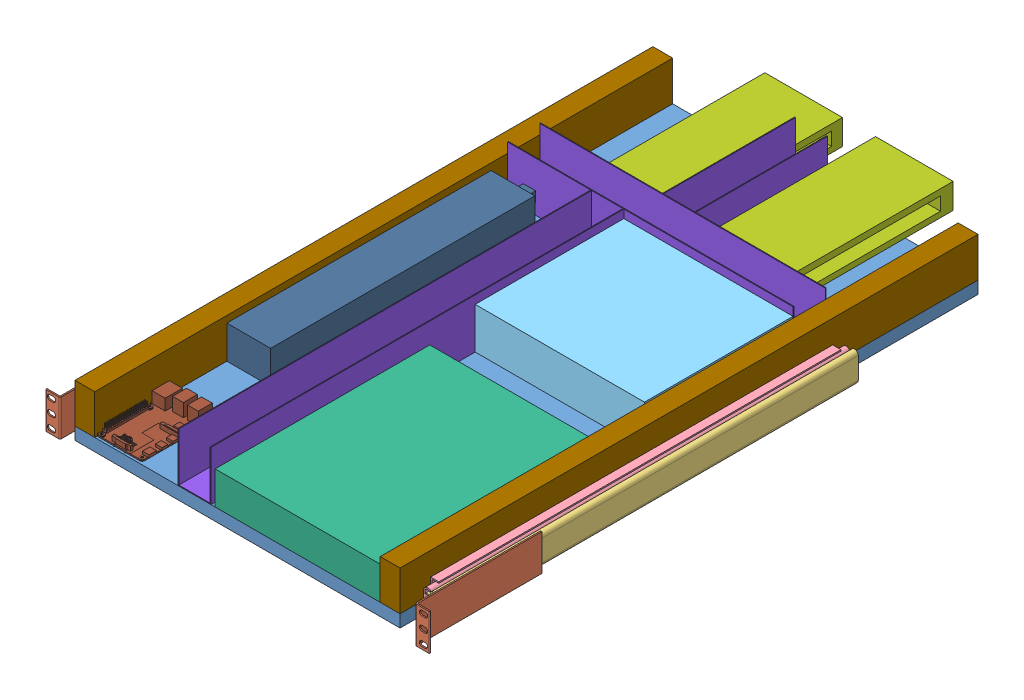
SolidWorks assembly Router-Schublade, configuration Standard. Lengths in mm.
Overall size (464.8 84.05 758).
20 component instances, 11 part files, 37 mates.
Components (placement in the parent):
- Platte-1: Platte [Standard] at (-201.5811 50.5043 900) size (393.8 15 700)
- Gleitschiene-Left-1: Gleitschiene-Left [Standard] at (-230.5216 -87.7457 847.2457) x (0 0 1) z (0 1 0) size (537 44.1 44)
  - winkel-1: winkel [Standard] at (51.9543 -6.5595 130.1) size (152.1 17.5 44)
  - Schine-1: Schine [Standard] at (-484.2457 10.9405 134.15) x (0 1 0) z (1 0 0) size (13.6 35 510)
  - Rolle-1: Rolle [Standard] at (-471.2457 35.9405 133.25) x (0 1 0) z (1 0 0) size (19.2 41.6 507)
- Gleitschiene-Right-1: Gleitschiene-Right [Standard] at (221.1594 215.5543 847.2457) x (0 0 1) z (0 -1 0) size (537 44.1 44.05)
  - winkel-1: winkel [Standard] at (51.9543 -6.5595 130.1) size (152.1 17.5 44)
  - Schine-1: Schine [Standard] at (-484.2457 10.9405 134.15) x (0 1 0) z (1 0 0) size (13.6 35 510)
  - Rolle-1: Rolle [Standard] at (15.7543 35.9405 170.05) x (0 1 0) z (-1 0 0) size (19.2 41.6 507)
- Modem-1: Modem [Standard] at (168.2189 115.5043 580) x (-1 0 0) z (0 -1 0) size (205 180 50)
- Router-1: Router [Standard] at (168.2189 65.5043 900) x (0 0 -1) z (1 0 0) size (260 40 200)
- Keystone Housing-1: Keystone Housing [Standard] at (-29.8854 65.5043 360) x (0 0 -1) z (1 0 0) size (218 30.5 94)
- Keystone Housing-2: Keystone Housing [Standard] at (10.1146 65.5043 142) x (0 0 1) z (-1 0 0) size (218 30.5 94)
- Kanal-1: Kanal [500] at (-56.7811 65.5043 400) size (40 60 500)
- Kanal-2: Kanal [160] at (-9.8854 65.5043 200) size (40 60 160)
- Seite-1: Seite [Standard] at (-201.5811 65.5043 200) size (24 48 700)
- Seite-2: Seite [Standard] at (168.2189 65.5043 200) size (24 48 700)
- Steckdose-1: Steckdose [Standard] at (-177.5811 65.5043 740) size (53 40 340)
- Kanal-3: Kanal [345,8] at (168.2189 65.5043 380) x (0 0 1) z (-1 0 0) size (40 60 345.8)
- Raspberry Pi 4 B-1: Raspberry Pi 4 B [默认] at (-135.4811 65.5043 851.3868) x (0 0 -1) z (0 1 0) size (86.92 58.6 19)
Mates (geometry in assembly coordinates):
- Deckungsgleich1: coincident anti-aligned: plane of Platte-1 through (-201.5811 65.5043 900) normal (-1 0 0); plane of Gleitschiene-Left-1/Rolle-1 through (-201.5811 45.5043 863) normal (1 0 0)
- Deckungsgleich2: coincident anti-aligned: plane of Platte-1 through (-201.5811 50.5043 900) normal (0 -1 0); plane of Gleitschiene-Left-1/Rolle-1 through (-192.9811 50.5043 863) normal (0 1 0)
- Abstand1: distance = 37 mm aligned: plane of Platte-1 through (-201.5811 65.5043 900) normal (0 0 1); plane of Gleitschiene-Left-1/Rolle-1 through (-194.5811 45.5043 863) normal (0 0 1)
- Deckungsgleich4: coincident anti-aligned: plane of Platte-1 through (192.2189 65.5043 900) normal (1 0 0); plane of Gleitschiene-Right-1/Rolle-1 through (192.2189 45.5043 376) normal (-1 0 0)
- Deckungsgleich5: coincident anti-aligned: plane of Platte-1 through (-201.5811 50.5043 900) normal (0 -1 0); plane of Gleitschiene-Right-1/Rolle-1 through (183.6189 50.5043 376) normal (0 1 0)
- Abstand2: distance = 37 mm aligned: plane of Platte-1 through (-201.5811 65.5043 900) normal (0 0 1); plane of Gleitschiene-Right-1/Rolle-1 through (185.2189 45.5043 863) normal (0 0 1)
- Deckungsgleich7: coincident anti-aligned: plane of Platte-1 through (-201.5811 65.5043 900) normal (0 1 0); plane of Modem-1 through (168.2189 65.5043 580) normal (0 -1 0)
- Deckungsgleich8: coincident anti-aligned: plane of Platte-1 through (-201.5811 65.5043 900) normal (0 1 0); plane of Router-1 through (168.2189 65.5043 900) normal (0 -1 0)
- Deckungsgleich11: coincident anti-aligned: plane of Platte-1 through (-201.5811 65.5043 900) normal (0 1 0); plane of Keystone Housing-2 through (10.1146 65.5043 142) normal (0 -1 0)
- Deckungsgleich15: coincident anti-aligned: plane of Platte-1 through (-201.5811 65.5043 900) normal (0 1 0); plane of Keystone Housing-1 through (-29.8854 65.5043 360) normal (0 -1 0)
- Deckungsgleich16: coincident anti-aligned: plane of Platte-1 through (-201.5811 65.5043 900) normal (0 1 0); plane of Kanal-1 through (-36.7811 65.5043 900) normal (0 -1 0)
- Deckungsgleich17: coincident aligned: plane of Platte-1 through (-201.5811 65.5043 900) normal (0 0 1); plane of Kanal-1 through (-56.7811 65.5043 900) normal (0 0 1)
- Deckungsgleich18: coincident anti-aligned: plane of Platte-1 through (-201.5811 65.5043 900) normal (0 1 0); plane of Kanal-2 through (10.1146 65.5043 360) normal (0 -1 0)
- Deckungsgleich19: coincident aligned: plane of Platte-1 through (-201.5811 65.5043 200) normal (0 0 -1); plane of Kanal-2 through (-9.8854 65.5043 200) normal (0 0 -1)
- Deckungsgleich20: coincident anti-aligned: plane of Platte-1 through (-201.5811 65.5043 900) normal (0 1 0); plane of Seite-1 through (-201.5811 65.5043 900) normal (0 -1 0)
- Deckungsgleich21: coincident anti-aligned: plane of Platte-1 through (-201.5811 65.5043 900) normal (0 1 0); plane of Seite-2 through (168.2189 65.5043 900) normal (0 -1 0)
- Deckungsgleich22: coincident aligned: plane of Platte-1 through (-201.5811 65.5043 900) normal (0 0 1); plane of Seite-2 through (168.2189 65.5043 900) normal (0 0 1)
- Deckungsgleich23: coincident aligned: plane of Platte-1 through (-201.5811 65.5043 900) normal (0 0 1); plane of Seite-1 through (-201.5811 65.5043 900) normal (0 0 1)
- Deckungsgleich24: coincident anti-aligned: plane of Gleitschiene-Left-1/Rolle-1 through (-201.5811 45.5043 863) normal (1 0 0); plane of Seite-1 through (-201.5811 65.5043 900) normal (-1 0 0)
- Deckungsgleich25: coincident anti-aligned: plane of Gleitschiene-Right-1/Rolle-1 through (192.2189 45.5043 376) normal (-1 0 0); plane of Seite-2 through (192.2189 65.5043 900) normal (1 0 0)
- Deckungsgleich27: coincident anti-aligned: plane of Router-1 through (168.2189 105.5043 900) normal (1 0 0); plane of Seite-2 through (168.2189 65.5043 900) normal (-1 0 0)
- Deckungsgleich28: coincident aligned: plane of Platte-1 through (-201.5811 65.5043 900) normal (0 0 1); plane of Router-1 through (168.2189 105.5043 900) normal (0 0 1)
- Deckungsgleich31: coincident anti-aligned: plane of Modem-1 through (168.2189 65.5043 580) normal (1 0 0); plane of Seite-2 through (168.2189 65.5043 900) normal (-1 0 0)
- Deckungsgleich32: coincident anti-aligned: plane of Platte-1 through (-201.5811 65.5043 900) normal (0 1 0); plane of Steckdose-1 through (-177.5811 65.5043 740) normal (0 -1 0)
- Deckungsgleich33: coincident anti-aligned: plane of Seite-1 through (-177.5811 65.5043 900) normal (1 0 0); plane of Steckdose-1 through (-177.5811 105.5043 740) normal (-1 0 0)
- Deckungsgleich34: coincident anti-aligned: plane of Platte-1 through (-201.5811 65.5043 900) normal (0 1 0); plane of Kanal-3 through (-177.5811 65.5043 400) normal (0 -1 0)
- Deckungsgleich35: coincident anti-aligned: plane of Seite-2 through (168.2189 65.5043 900) normal (-1 0 0); plane of Kanal-3 through (168.2189 65.5043 380) normal (1 0 0)
- Deckungsgleich36: coincident anti-aligned: plane of Platte-1 through (-201.5811 65.5043 900) normal (0 1 0); plane of Raspberry Pi 4 B-1 through (-151.5742 65.5043 886.8876) normal (0 -1 0)
- Deckungsgleich37: coincident anti-aligned: plane of Seite-1 through (-177.5811 65.5043 900) normal (1 0 0); plane of Raspberry Pi 4 B-1 through (-177.5811 67.3049 837.8644) normal (-1 0 0)
- Deckungsgleich38: coincident anti-aligned: plane of Kanal-1 through (-56.7811 65.5043 400) normal (0 0 -1); plane of Kanal-3 through (-177.5811 125.5043 400) normal (0 0 1)
- Deckungsgleich39: coincident anti-aligned: plane of Modem-1 through (-36.7811 65.5043 580) normal (-1 0 0); plane of Kanal-1 through (-36.7811 125.5043 900) normal (1 0 0)
- Deckungsgleich40: coincident anti-aligned: plane of Modem-1 through (168.2189 65.5043 400) normal (0 0 -1); plane of Kanal-3 through (-177.5811 125.5043 400) normal (0 0 1)
- Deckungsgleich41: coincident anti-aligned: plane of Steckdose-1 through (-158.5811 105.5043 400) normal (0 0 -1); plane of Kanal-3 through (-177.5811 125.5043 400) normal (0 0 1)
- Deckungsgleich42: coincident anti-aligned: plane of Keystone Housing-1 through (-29.8854 96.0043 360) normal (0 0 1); plane of Kanal-3 through (-177.5811 65.5043 360) normal (0 0 -1)
- Deckungsgleich43: coincident anti-aligned: plane of Keystone Housing-2 through (10.1146 96.0043 360) normal (0 0 1); plane of Kanal-3 through (-177.5811 65.5043 360) normal (0 0 -1)
- Deckungsgleich44: coincident anti-aligned: plane of Keystone Housing-1 through (-29.8854 96.0043 360) normal (1 0 0); plane of Kanal-2 through (-29.8854 65.5043 360) normal (-1 0 0)
- Deckungsgleich45: coincident anti-aligned: plane of Keystone Housing-2 through (10.1146 96.0043 142) normal (-1 0 0); plane of Kanal-2 through (10.1146 125.5043 360) normal (1 0 0)
